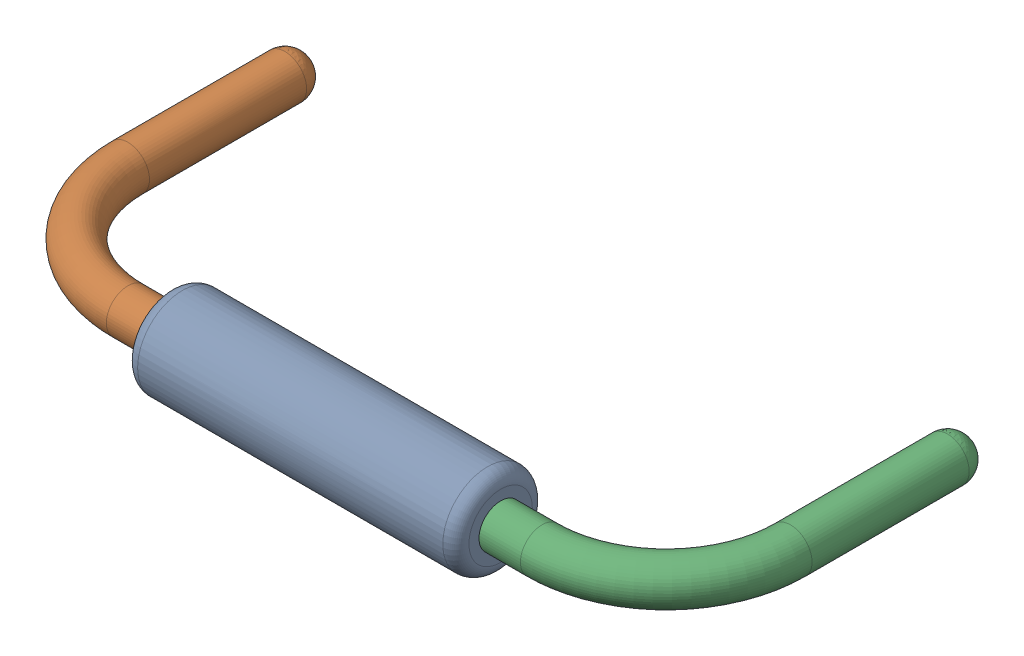
SolidWorks assembly R6, configuration Défaut. Lengths in mm.
Overall size (10.82 1.37 5.33).
4 component instances, 3 part files, 0 mates.
Components (placement in the parent):
- Open CASCADE STEP translator 6.8 1.10.1-1: Open CASCADE STEP translator 6.8 1.10.1 [Défaut] at origin size (10.82 1.37 5.33)
  - Body_1_7-1: Body_1_7 [Défaut] at origin size (5.08 1.37 1.37)
  - Pin_1_4-1: Pin_1_4 [Défaut] at origin size (3.2 0.66 4.98)
  - Pin_2_4-1: Pin_2_4 [Défaut] at (20.32 0 0) x (-1 0 0) z (0 0 1) size (3.2 0.66 4.98)
